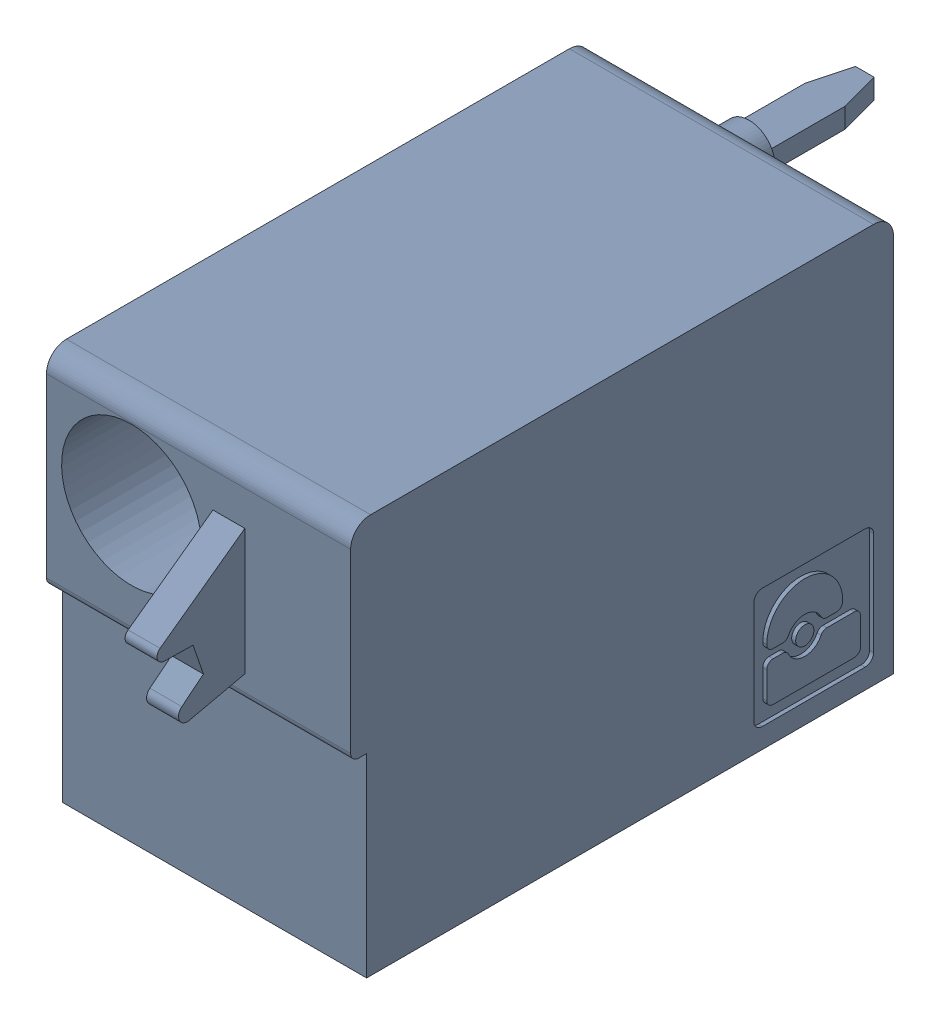
SolidWorks assembly J25, configuration Default. Lengths in mm.
Overall size (7.62 10 19.2).
2 component instances, 1 part files, 0 mates.
Components (placement in the parent):
- 1790487-1: 1790487 [Default] at (46.125 -15.67 -10.6) x (0 1 0) z (1 0 0) size (10 19.2 7.62)
  - ffkdsa1-v2-7.62-1: ffkdsa1-v2-7.62 [Default] at (-15.6914 -27.508 9.12) x (0 -1 0) z (0 0 1) size (19.2 10 7.62)
